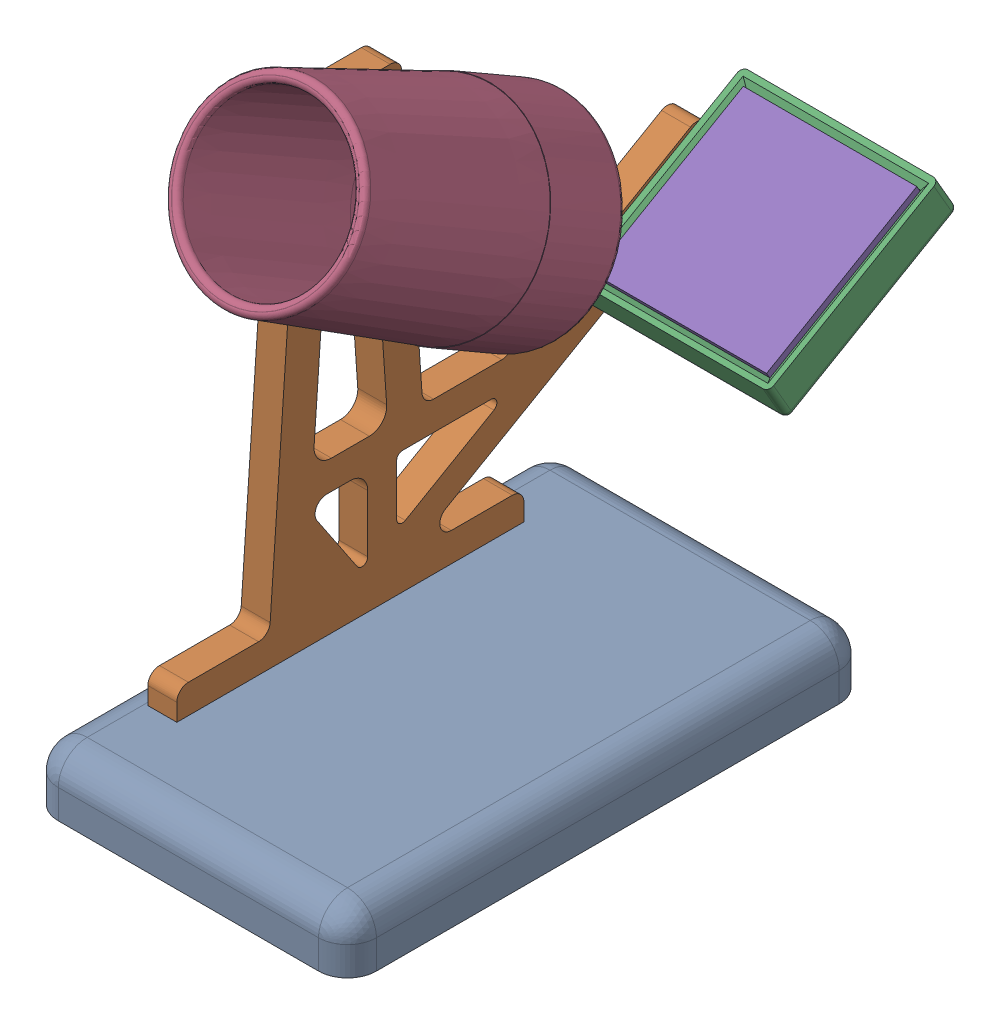
SolidWorks assembly 颗粒对焦器_装配体, configuration Default. Lengths in mm.
Overall size (55 113.23 116.25).
6 component instances, 6 part files, 14 mates.
Components (placement in the parent):
- 底座-1: 底座 [默认] at origin size (55 10 90)
- 支架-1: 支架 [默认] at (-17 5 -25) x (0 0 1) z (0 -1 0) size (94.79 5 85.08)
- 镜片平台-1: 镜片平台 [默认] at (-22 42.2475 -52.194) x (1 0 0) z (0 -0.5 0.866025) size (39 7 34)
- 磨砂屏-目镜座-2: 磨砂屏-目镜座 [默认] at (0 73.5123 -11.622) x (1 0 0) z (0 -0.866025 0.5) size (39 50 34)
- 镜面-1: 镜面 [默认] at (0 48.9583 -53.9775) x (1 0 0) z (0 -0.5 0.866025) size (30 2.08 30)
- 单面磨砂片-1: 单面磨砂片 [默认] at (0.0764 73.5682 -11.6542) x (1 0 0) z (0 -0.866025 0.5) size (30 1.7 30)
Mates (geometry in assembly coordinates):
- 重合1: coincident anti-aligned: plane of 底座-1 through (0 5 0) normal (0 1 0); plane of 支架-1 through (-22 5 -25) normal (0 -1 0)
- 重合2: coincident anti-aligned: plane of 底座-1 through (-22 5 0) normal (1 0 0); plane of 支架-1 through (-22 5 -25) normal (-1 0 0)
- 重合3: coincident anti-aligned: plane of 底座-1 through (0 5 -25) normal (0 0 1); plane of 支架-1 through (-22 10 -25) normal (0 0 -1)
- 重合4: coincident aligned: plane of 支架-1 through (-22 5 -25) normal (-1 0 0); plane of 镜片平台-1 through (-22 46.5776 -49.694) normal (-1 0 0)
- 重合5: coincident anti-aligned: plane of 支架-1 through (-17 51.5776 -58.3543) normal (0 -0.5 0.866025); plane of 镜片平台-1 through (-22 51.5776 -58.3543) normal (0 0.5 -0.866025)
- 重合6: coincident anti-aligned: plane of 支架-1 through (-17 46.5776 -49.694) normal (0 -0.866025 -0.5); plane of 镜片平台-1 through (-22 46.5776 -49.694) normal (0 0.866025 0.5)
- 重合7: coincident aligned: plane of 支架-1 through (-22 5 -25) normal (-1 0 0); plane of 磨砂屏-目镜座-2 through (-22 82.8425 -5.4617) normal (-1 0 0)
- 重合8: coincident anti-aligned: plane of 支架-1 through (-17 32.9209 23.3605) normal (0 0.5 0.866025); plane of 磨砂屏-目镜座-2 through (0 78.5123 -2.9617) normal (0 -0.5 -0.866025)
- 重合9: coincident anti-aligned: plane of 支架-1 through (-17 46.2613 -48.8222) normal (0 0.866025 -0.5); plane of 磨砂屏-目镜座-2 through (-22 74.1822 -0.4617) normal (0 -0.866025 0.5)
- 重合10: coincident anti-aligned: plane of 镜片平台-1 through (-22 46.5083 -49.734) normal (0 0.866025 0.5); plane of 镜面-1 through (0 48.9583 -53.9775) normal (0 -0.866025 -0.5)
- 重合11: coincident anti-aligned: plane of 镜片平台-1 through (-15 56.5083 -67.0545) normal (1 0 0); plane of 镜面-1 through (-15 43.2597 -39.9472) normal (-1 0 0)
- 重合12: coincident anti-aligned: plane of 镜片平台-1 through (-15 41.4583 -40.9872) normal (0 0.5 -0.866025); plane of 镜面-1 through (-15 43.2597 -39.9472) normal (0 -0.5 0.866025)
- 重合13: coincident anti-aligned: plane of 磨砂屏-目镜座-2 through (0 74.3623 -10.1497) normal (0 -0.5 -0.866025); plane of 单面磨砂片-1 through (0.0764 74.4182 -10.182) normal (0 0.5 0.866025)
- 相切1: tangent aligned: cylinder of 磨砂屏-目镜座-2 through (0 74.3623 -10.1497) axis (0 -0.5 -0.866025) radius 15.1; cylinder of 单面磨砂片-1 through (0.0764 74.4182 -10.182) axis (0 -0.5 -0.866025) radius 15
